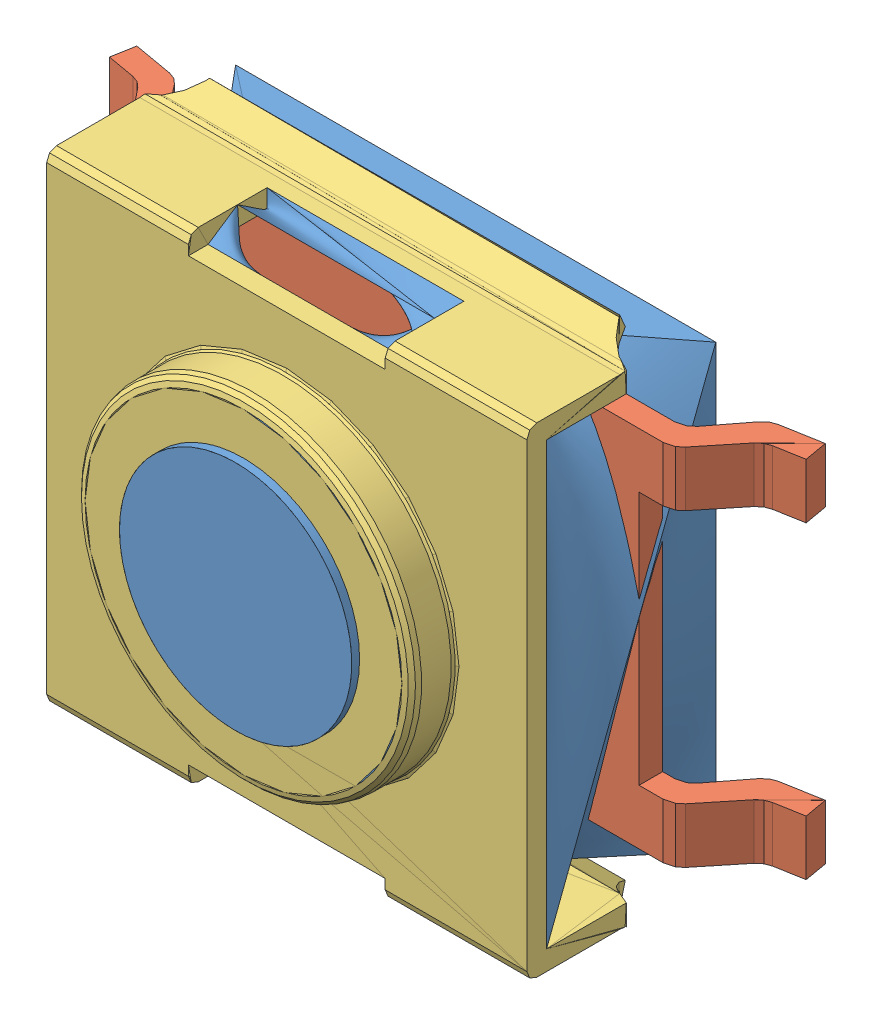
SolidWorks assembly 6MM_SWITCH, configuration Default. Lengths in mm.
Overall size (8.92 6.58 3.14).
3 component instances, 3 part files, 0 mates.
Components (placement in the parent):
- _1-1: _1 [Default] at (0 0 0.0343) size (6.15 6.15 3.07)
- _2-1: _2 [Default] at (0 0 -1.0585) size (8.92 4.66 1.03)
- _3-1: _3 [Default] at (0 0 0.3116) size (6.16 6.58 2.49)
